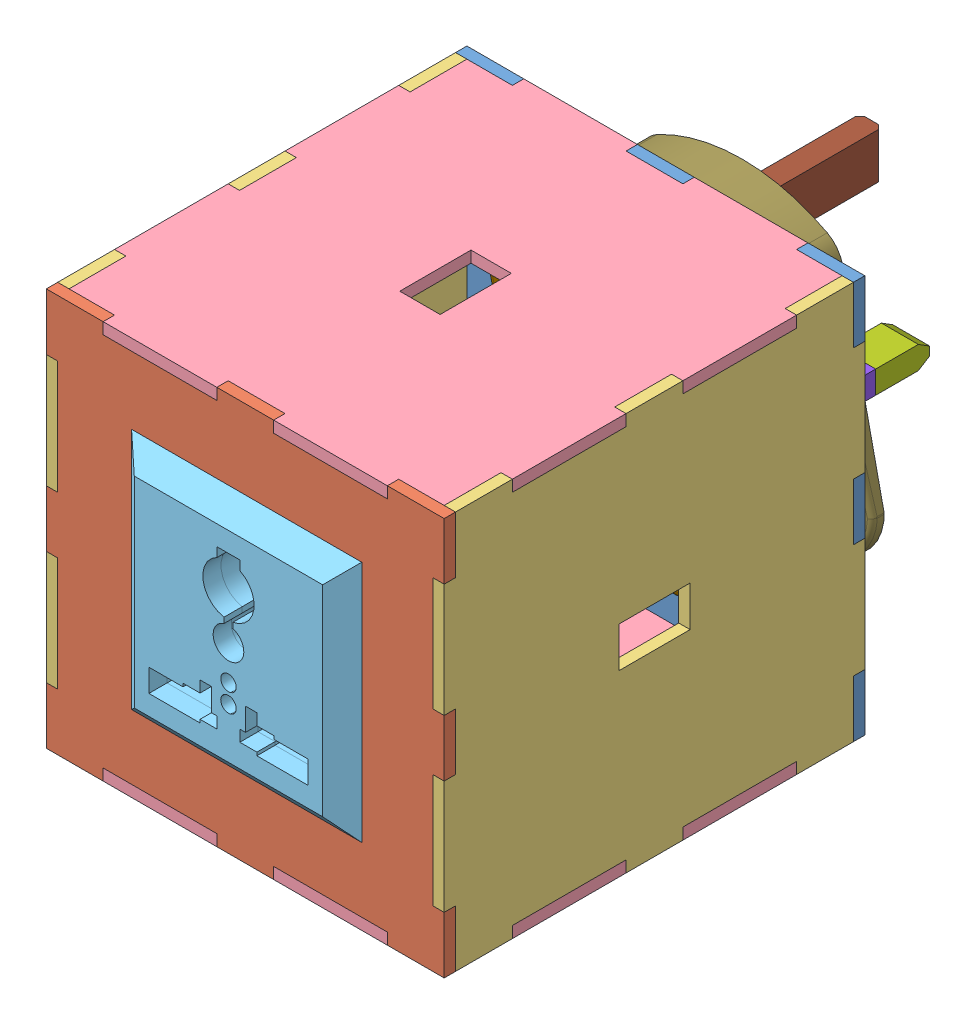
SolidWorks assembly Base_Assem, configuration Default. Lengths in mm.
Overall size (70 70 113.44).
76 component instances, 72 part files, 22 mates.
Components (placement in the parent):
- Base_Back-1: Base_Back [Default] at (-30.901 -7.255 -12.7399) size (70 70 2)
- Base_Front-1: Base_Front [Default] at (-30.901 -7.255 59.2601) size (70 70 2)
- Base_LR-1: Base_LR [Default] at (2.099 -7.255 22.2601) x (0 0 1) z (-1 0 0) size (74 70 2)
- Base_LR-2: Base_LR [Default] at (-63.901 -7.255 22.2601) x (0 0 -1) z (1 0 0) size (74 70 2)
- Base_TB-3: Base_TB [Default] at (-30.901 27.745 22.2601) x (1 0 0) z (0 -1 0) size (70 74 2)
- Base_TB-4: Base_TB [Default] at (-30.901 -40.255 22.2601) x (1 0 0) z (0 -1 0) size (70 74 2)
- Base_Plug_Front-1: Base_Plug_Front [Default] at (-30.651 -7.505 59.2601) x (-1 0 0) z (0 0 1) size (40.5 42.7 31.7)
- 220ACto5VDC-1: 220ACto5VDC [Varsayılan] at (-40.9559 -40.255 23.618) size (21 16.42 30)
- UK 3 PIN PLUG-2: UK 3 PIN PLUG [Default] at (-131.476 -98.255 -25.2342) size (50.06 51.74 44.47)
  - UK 3 PIN PLUG.stp-1: UK 3 PIN PLUG.stp [Default] at origin size (348.87 192.57 64.06)
    - Body1.stp-1: Body1.stp [Default] at origin size (6.5 6.5 24.5)
    - Body2.stp-1: Body2.stp [Default] at origin size (6.5 4 11)
    - Body3.stp-1: Body3.stp [Default] at origin size (6.5 4 11)
    - Body4.stp-1: Body4.stp [Default] at origin size (6.5 6.5 28.5)
    - Body5.stp-1: Body5.stp [Default] at origin size (6.5 8 33.5)
    - Body6.stp-1: Body6.stp [Default] at origin size (50.06 51.5 16.75)
    - Body7.stp-1: Body7.stp [Default] at origin size (0.2 24 0.2)
    - Body8.stp-1: Body8.stp [Default] at origin size (6.5 24.92 6.5)
    - Body9.stp-1: Body9.stp [Default] at origin size (8 13 13)
    - Body10.stp-1: Body10.stp [Default] at origin size (4 4 8.5)
    - Body11.stp-1: Body11.stp [Default] at origin size (12.5 5.5 6.25)
    - Body12.stp-1: Body12.stp [Default] at origin size (5 5 15.5)
    - Body13.stp-1: Body13.stp [Default] at origin size (5 5 15.5)
    - Body14.stp-1: Body14.stp [Default] at origin size (4 4 8.5)
    - Body15.stp-1: Body15.stp [Default] at origin size (24 6.5 7)
    - Body16.stp-1: Body16.stp [Default] at origin size (8 6.5 10)
    - Body17.stp-1: Body17.stp [Default] at origin size (6 5.92 15)
    - Body18.stp-1: Body18.stp [Default] at origin size (5.7 14.92 5.7)
    - Body19.stp-1: Body19.stp [Default] at origin size (4 4 8.5)
    - Body20.stp-1: Body20.stp [Default] at origin size (6.06 16.42 3.6)
    - Body21.stp-1: Body21.stp [Default] at origin size (48.93 51.66 2.66)
    - Body22.stp-1: Body22.stp [Default] at origin size (35.5 51.4 12.19)
    - Body23.stp-1: Body23.stp [Default] at origin size (83.93 44.02 52.79) (hidden)
    - Body24.stp-1: Body24.stp [Default] at origin size (2.51 25.01 2.51) (hidden)
    - Body25.stp-1: Body25.stp [Default] at origin size (2.51 25.01 2.51) (hidden)
    - Body26.stp-1: Body26.stp [Default] at origin size (2.5 45 2.5) (hidden)
    - Body27.stp-1: Body27.stp [Default] at origin size (2.5 35 2.5) (hidden)
    - Body28.stp-1: Body28.stp [Default] at origin size (1.5 6.5 1.5) (hidden)
    - Body29.stp-1: Body29.stp [Default] at origin size (1.5 6.5 1.5) (hidden)
    - Body30.stp-1: Body30.stp [Default] at origin size (1.5 6.5 1.5) (hidden)
    - Body31.stp-1: Body31.stp [Default] at origin size (1.5 6.5 1.5)
    - Body32.stp-1: Body32.stp [Default] at origin size (6.5 1.5 1.5)
    - Body33.stp-1: Body33.stp [Default] at origin size (1.5 6.5 1.5)
    - Body34.stp-1: Body34.stp [Default] at origin size (11.77 18.41 2.7)
    - Body35.stp-1: Body35.stp [Default] at origin
    - Body36.stp-1: Body36.stp [Default] at origin
    - Body37.stp-1: Body37.stp [Default] at origin size (108.97 154.57 46.33) (hidden)
    - Body38.stp-1: Body38.stp [Default] at origin size (24.5 6.5 6.5) (hidden)
    - Body39.stp-1: Body39.stp [Default] at origin size (11 4 6.5) (hidden)
    - Body40.stp-1: Body40.stp [Default] at origin size (11 4 6.5) (hidden)
    - Body41.stp-1: Body41.stp [Default] at origin size (28.5 6.5 6.5) (hidden)
    - Body42.stp-1: Body42.stp [Default] at origin size (33.5 8 6.5) (hidden)
    - Body43.stp-1: Body43.stp [Default] at origin size (16.75 51.5 50.06) (hidden)
    - Body44.stp-1: Body44.stp [Default] at origin size (0.2 24 0.2) (hidden)
    - Body45.stp-1: Body45.stp [Default] at origin size (6.5 24.92 6.5) (hidden)
    - Body46.stp-1: Body46.stp [Default] at origin size (13 13 8) (hidden)
    - Body47.stp-1: Body47.stp [Default] at origin size (8.5 4 4) (hidden)
    - Body48.stp-1: Body48.stp [Default] at origin size (6.25 5.5 12.5) (hidden)
    - Body49.stp-1: Body49.stp [Default] at origin size (15.5 5 5) (hidden)
    - Body50.stp-1: Body50.stp [Default] at origin size (15.5 5 5) (hidden)
    - Body51.stp-1: Body51.stp [Default] at origin size (8.5 4 4) (hidden)
    - Body52.stp-1: Body52.stp [Default] at origin size (7 6.5 24) (hidden)
    - Body53.stp-1: Body53.stp [Default] at origin size (10 6.5 8) (hidden)
    - Body54.stp-1: Body54.stp [Default] at origin size (15 5.92 6) (hidden)
    - Body55.stp-1: Body55.stp [Default] at origin size (5.7 14.92 5.7) (hidden)
    - Body56.stp-1: Body56.stp [Default] at origin size (8.5 4 4) (hidden)
    - Body57.stp-1: Body57.stp [Default] at origin size (3.6 16.42 6.06) (hidden)
    - Body58.stp-1: Body58.stp [Default] at origin size (2.67 51.64 48.93) (hidden)
    - Body59.stp-1: Body59.stp [Default] at origin size (12.19 51.4 35.5) (hidden)
    - Body60.stp-1: Body60.stp [Default] at origin size (1.5 6.5 1.5) (hidden)
    - Body61.stp-1: Body61.stp [Default] at origin size (1.5 1.5 6.5) (hidden)
    - Body62.stp-1: Body62.stp [Default] at origin size (1.5 6.5 1.5) (hidden)
    - Body63.stp-1: Body63.stp [Default] at origin size (2.7 18.41 11.77) (hidden)
    - Body64.stp-1: Body64.stp [Default] at origin
    - Body65.stp-1: Body65.stp [Default] at origin
    - Body66.stp-1: Body66.stp [Default] at origin size (8 24.26 8) (hidden)
Mates (geometry in assembly coordinates):
- Coincident1: coincident aligned: plane of Base_Front-1 through (-65.901 -42.255 57.2601) normal (-1 0 0); plane of Base_LR-2 through (-65.901 -7.255 22.2601) normal (-1 0 0)
- Coincident2: coincident aligned: plane of Base_Front-1 through (4.099 -42.255 57.2601) normal (1 0 0); plane of Base_LR-1 through (4.099 -7.255 22.2601) normal (1 0 0)
- Coincident11: coincident aligned: plane of Base_Front-1 through (-30.901 -7.255 59.2601) normal (0 0 1); plane of Base_LR-2 through (-65.901 -7.255 59.2601) normal (0 0 1)
- Coincident12: coincident aligned: plane of Base_Front-1 through (-65.901 27.745 57.2601) normal (0 1 0); plane of Base_LR-2 through (-65.901 27.745 57.2601) normal (0 1 0)
- Coincident13: coincident aligned: plane of Base_Front-1 through (-65.901 27.745 57.2601) normal (0 1 0); plane of Base_LR-1 through (4.099 27.745 -12.7399) normal (0 1 0)
- Coincident14: coincident aligned: plane of Base_Front-1 through (-30.901 -7.255 59.2601) normal (0 0 1); plane of Base_LR-1 through (4.099 -7.255 59.2601) normal (0 0 1)
- Coincident15: coincident aligned: plane of Base_Back-1 through (-30.901 -7.255 -14.7399) normal (0 0 -1); plane of Base_LR-1 through (4.099 -7.255 -14.7399) normal (0 0 -1)
- Coincident16: coincident aligned: plane of Base_Back-1 through (-65.901 -42.255 -14.7399) normal (-1 0 0); plane of Base_LR-2 through (-65.901 -7.255 22.2601) normal (-1 0 0)
- Coincident17: coincident aligned: plane of Base_Back-1 through (-65.901 27.745 -14.7399) normal (0 1 0); plane of Base_LR-2 through (-65.901 27.745 57.2601) normal (0 1 0)
- Coincident21: coincident aligned: plane of Base_LR-2 through (-65.901 27.745 57.2601) normal (0 1 0); plane of Base_TB-3 through (-30.901 27.745 22.2601) normal (0 1 0)
- Coincident23: coincident anti-aligned: plane of Base_Front-1 through (-30.901 -7.255 57.2601) normal (0 0 -1); plane of Base_TB-3 through (-63.901 25.745 57.2601) normal (0 0 1)
- Coincident24: coincident aligned: plane of Base_LR-2 through (-65.901 -7.255 22.2601) normal (-1 0 0); plane of Base_TB-3 through (-65.901 25.745 22.2601) normal (-1 0 0)
- Coincident25: coincident aligned: plane of Base_LR-2 through (-65.901 -42.255 57.2601) normal (0 -1 0); plane of Base_TB-4 through (-30.901 -42.255 22.2601) normal (0 -1 0)
- Coincident26: coincident aligned: plane of Base_Front-1 through (-30.901 -7.255 59.2601) normal (0 0 1); plane of Base_TB-4 through (-30.901 -42.255 59.2601) normal (0 0 1)
- Coincident27: coincident aligned: plane of Base_LR-1 through (4.099 -7.255 22.2601) normal (1 0 0); plane of Base_TB-4 through (4.099 -42.255 22.2601) normal (1 0 0)
- Coincident28: coincident anti-aligned: plane of Base_Front-1 through (-30.901 -7.255 59.2601) normal (0 0 1); plane of Base_Plug_Front-1 through (-30.651 -7.505 59.2601) normal (0 0 -1)
- Coincident29: coincident anti-aligned: plane of Base_Front-1 through (-48.151 10.745 57.2601) normal (0 -1 0); plane of Base_Plug_Front-1 through (-48.151 10.745 35.7601) normal (0 1 0)
- Coincident30: coincident anti-aligned: plane of Base_Front-1 through (-48.151 -25.255 57.2601) normal (1 0 0); plane of Base_Plug_Front-1 through (-48.151 -25.755 35.7601) normal (-1 0 0)
- Coincident31: coincident anti-aligned: plane of Base_Back-1 through (-48.226 -7.255 -4.7399) normal (1 0 0); plane of UK 3 PIN PLUG-2/UK 3 PIN PLUG.stp-1/Body22.stp-1 through (-48.226 -22.6021 -19.2342) normal (-1 0 0)
- Coincident32: coincident anti-aligned: plane of Base_TB-4 through (-30.901 -40.255 22.2601) normal (0 1 0); plane of 220ACto5VDC-1 through (-40.9559 -40.255 23.618) normal (0 -1 0)
- Coincident33: coincident anti-aligned: plane of Base_Back-1 through (-48.226 -7.255 -4.7399) normal (1 0 0); plane of UK 3 PIN PLUG-2/UK 3 PIN PLUG.stp-1/Body22.stp-1 through (-48.226 -22.6021 -19.2342) normal (-1 0 0)
- Coincident34: coincident anti-aligned: plane of Base_Back-1 through (-30.901 -29.755 -4.7399) normal (0 1 0); plane of UK 3 PIN PLUG-2/UK 3 PIN PLUG.stp-1/Body6.stp-1 through (-19.8575 -29.755 -27.7342) normal (0 -1 0)
